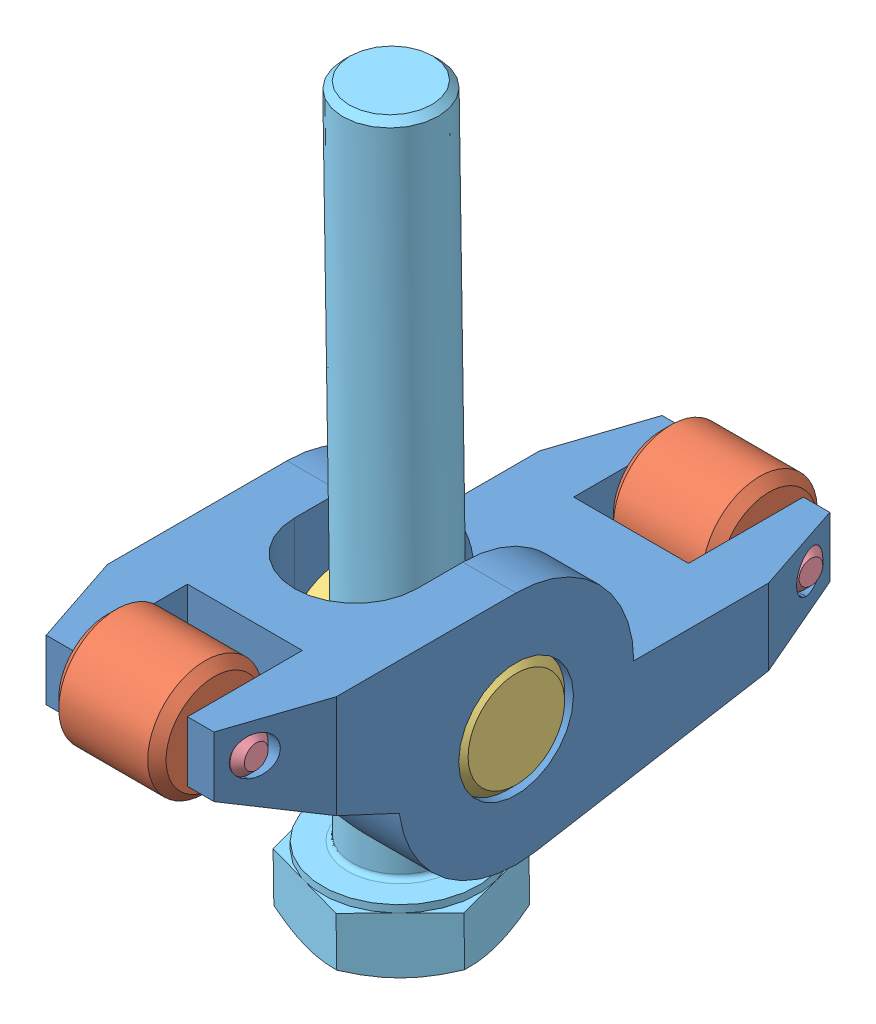
SolidWorks assembly Assem1, configuration Default. Lengths in mm.
Overall size (19.05 60.56 55.56).
7 component instances, 5 part files, 12 mates.
Components (placement in the parent):
- 7 rocker arm USED-1: 7 rocker arm USED [Default] at (6.2377 28.2795 44.9082) size (19 19.53 51.1)
- 7.1 rocker arm roll-1: 7.1 rocker arm roll [Default] at (6.2377 35.5045 64.8982) size (8.9 9.53 9.53)
- 7.2 rocker arm pin 1-1: 7.2 rocker arm pin 1 [Default] at (6.2377 28.2795 44.9082) x (1 0 0) z (0 -0.015134 0.999885) size (19.05 9.53 9.53)
- 7.1 rocker arm roll-2: 7.1 rocker arm roll [Default] at (6.2377 25.7395 18.8732) size (8.9 9.53 9.53)
- 7.3 rocker arm pin 2-1: 7.3 rocker arm pin 2 [Default] at (6.2377 35.5045 64.8982) x (1 0 0) z (0 0.994959 -0.100283) size (15.87 3.17 3.17)
- 7.3 rocker arm pin 2-2: 7.3 rocker arm pin 2 [Default] at (6.2377 25.7395 18.8732) x (1 0 0) z (0 -0.747773 0.663955) size (15.87 3.17 3.17)
- hex screw gradeab fine_iso-5: hex screw gradeab fine_iso [ISO 8676 - M8x1.0 x 55-N] at (6.2377 10.2778 44.8858) x (0 0.999885 0.015134) z (0.968285 0.003781 -0.249818) size (60.3 15.01 13)
Mates (geometry in assembly coordinates):
- Width1: width anti-aligned: plane of 7.1 rocker arm roll-2 through (1.7877 25.7395 18.8732) normal (-1 0 0); plane of 7 rocker arm USED-1 through (10.6877 25.7395 18.8732) normal (1 0 0); plane of 7.1 rocker arm roll-2 through (1.4727 11.2795 25.8632) normal (1 0 0); plane of 7 rocker arm USED-1 through (11.0027 11.2795 25.8632) normal (-1 0 0)
- Concentric1: concentric anti-aligned: cylinder of 7 rocker arm USED-1 through (-10.7623 25.7395 18.8732) axis (1 0 0) radius 1.59; cylinder of 7.1 rocker arm roll-2 through (10.6877 25.7395 18.8732) axis (-1 0 0) radius 1.59
- Width2: width anti-aligned: plane of 7.2 rocker arm pin 1-1 through (15.7627 28.2795 44.9082) normal (1 0 0); plane of 7 rocker arm USED-1 through (-3.2873 28.2795 44.9082) normal (-1 0 0); plane of 7.2 rocker arm pin 1-1 through (-3.2623 28.2795 44.9082) normal (-1 0 0); plane of 7 rocker arm USED-1 through (15.7377 28.2795 44.9082) normal (1 0 0)
- Concentric2: concentric aligned: cylinder of 7 rocker arm USED-1 through (15.7377 28.2795 44.9082) axis (-1 0 0) radius 4.765; cylinder of 7.2 rocker arm pin 1-1 through (15.7627 28.2795 44.9082) axis (-1 0 0) radius 4.765
- Width3: width aligned: plane of 7.1 rocker arm roll-1 through (10.6877 35.5045 64.8982) normal (1 0 0); plane of 7 rocker arm USED-1 through (1.7877 35.5045 64.8982) normal (-1 0 0); plane of 7.1 rocker arm roll-1 through (1.4727 11.2795 57.9082) normal (1 0 0); plane of 7 rocker arm USED-1 through (11.0027 11.2795 57.9082) normal (-1 0 0)
- Concentric3: concentric anti-aligned: cylinder of 7 rocker arm USED-1 through (-10.7623 35.5045 64.8982) axis (1 0 0) radius 1.59; cylinder of 7.1 rocker arm roll-1 through (10.6877 35.5045 64.8982) axis (-1 0 0) radius 1.59
- Concentric4: concentric anti-aligned: cylinder of 7 rocker arm USED-1 through (-10.7623 35.5045 64.8982) axis (1 0 0) radius 1.59; cylinder of 7.3 rocker arm pin 2-1 through (14.1727 35.5045 64.8982) axis (-1 0 0) radius 1.585
- Width4: width aligned: plane of 7.3 rocker arm pin 2-1 through (14.1727 35.5045 64.8982) normal (1 0 0); plane of 7 rocker arm USED-1 through (-1.6973 35.5045 64.8982) normal (-1 0 0); plane of 7.3 rocker arm pin 2-1 through (1.4727 11.2795 57.9082) normal (1 0 0); plane of 7 rocker arm USED-1 through (11.0027 11.2795 57.9082) normal (-1 0 0)
- Concentric5: concentric anti-aligned: cylinder of 7 rocker arm USED-1 through (-10.7623 25.7395 18.8732) axis (1 0 0) radius 1.59; cylinder of 7.3 rocker arm pin 2-2 through (14.1727 25.7395 18.8732) axis (-1 0 0) radius 1.585
- Width5: width anti-aligned: plane of 7.3 rocker arm pin 2-2 through (14.1727 25.7395 18.8732) normal (1 0 0); plane of 7 rocker arm USED-1 through (-1.6973 25.7395 18.8732) normal (-1 0 0); plane of 7.3 rocker arm pin 2-2 through (11.0027 11.2795 25.8632) normal (-1 0 0); plane of 7 rocker arm USED-1 through (1.4727 11.2795 25.8632) normal (1 0 0)
- Concentric8: concentric anti-aligned: cylinder of 7.2 rocker arm pin 1-1 through (6.2377 18.7518 45.014) axis (0 0.999885 0.015134) radius 3.43; cylinder of hex screw gradeab fine_iso-5 through (6.2377 0.9085 44.744) axis (0 -0.999885 -0.015134) radius 4
- Distance1: distance = 12.7 mm aligned: plane of 7.2 rocker arm pin 1-1 through (6.2377 28.2795 44.9082) normal (0 0.999885 0.015134); plane of hex screw gradeab fine_iso-5 through (8.1129 15.4672 52.2327) normal (0 0.999885 0.015134)
